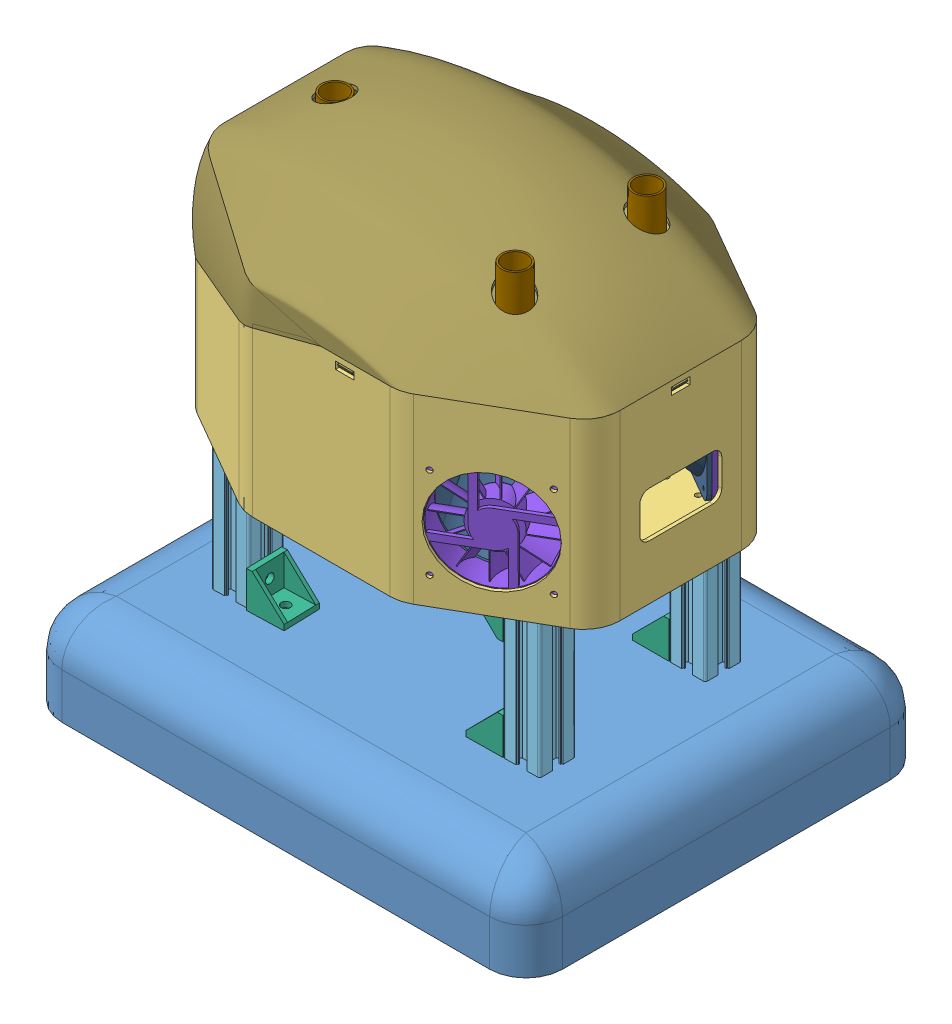
SolidWorks assembly Case_gases, configuration Predeterminado. Lengths in mm.
Overall size (275 288.19 220).
33 component instances, 12 part files, 60 mates.
Components (placement in the parent):
- Unitree_base-1: Unitree_base [Predeterminado] at origin size (275 50 220)
- arduino uno-1: arduino uno [Predeterminado] at (57.7112 103.65 32.423) size (53.34 15.25 74.93)
- Box_half-1: Box_half [Predeterminado] at (0 100 0) x (0 0 1) z (-1 0 0) size (170 100 225)
- Jetson Xavier NX DevKit LQ-1: Jetson Xavier NX DevKit LQ [Predeterminado] at (-44.3673 115.16 33.4874) x (0 0 -1) z (0 1 0) size (103 91.06 34.66)
- 2020_180mm-1: 2020_180mm [Valor predeterminado] at (80.2485 62.5 45.4943) x (-0.999929 0 0.011892) z (0 -1 0) size (20 20 75)
- Esquina2020-1: Esquina2020 [Predeterminado] at (60.2499 100 45.7322) x (0.011892 0 0.999929) z (0.999929 0 -0.011892) size (20 20 20)
- 2020_180mm-2: 2020_180mm [Valor predeterminado] at (-80.25 62.5 -45.75) x (1 0 0) z (0 -1 0) size (20 20 75)
- 2020_180mm-3: 2020_180mm [Valor predeterminado] at (80.25 62.5 -45.75) x (1 0 0) z (0 -1 0) size (20 20 75)
- 2020_180mm-4: 2020_180mm [Valor predeterminado] at (-80.281 62.5 45.0648) x (0.999533 0 -0.030564) z (0 -1 0) size (20 20 75)
- Esquina2020-2: Esquina2020 [Predeterminado] at (60.2499 25 45.7322) x (-0.011892 0 -0.999929) z (0.999929 0 -0.011892) size (20 20 20)
- Esquina2020-3: Esquina2020 [Predeterminado] at (-60.2903 100 44.4535) x (-0.030564 0 -0.999533) z (-0.999533 0 0.030564) size (20 20 20)
- Esquina2020-4: Esquina2020 [Predeterminado] at (-60.2493 25 45.7958) x (0.030564 0 0.999533) z (-0.999533 0 0.030564) size (20 20 20)
- Esquina2020-5: Esquina2020 [Predeterminado] at (60.25 25 -45.75) x (0 0 -1) z (1 0 0) size (20 20 20)
- Esquina2020-6: Esquina2020 [Predeterminado] at (-60.25 25 -45.75) x (0 0 1) z (-1 0 0) size (20 20 20)
- Esquina2020-7: Esquina2020 [Predeterminado] at (-60.25 100 -45.75) x (0 0 -1) z (-1 0 0) size (20 20 20)
- Esquina2020-8: Esquina2020 [Predeterminado] at (60.25 100 -45.75) x (0 0 1) z (1 0 0) size (20 20 20)
- tca9548a-1: tca9548a [Predeterminado] at (13.0283 102.399 -58.6097) size (21.5 2.4 31.5)
- 60x60x15 12V fan-2: 60x60x15 12V fan [Default] at (68.7162 145.2772 -50.6487) x (-0.866025 0 -0.5) z (0.5 0 -0.866025) size (60 60 15)
- 60x60x15 12V fan-3: 60x60x15 12V fan [Default] at (76.2162 145.2772 63.639) x (-0.866025 0 0.5) z (-0.5 0 -0.866025) size (60 60 15)
- Sub_salida_aire-1: Sub_salida_aire [Predeterminado] at (66.6795 140 51.8246) x (0 1 0) z (-0.866025 0 0.5) size (137.24 27.54 60.72)
  - ducto_sensor-1: ducto_sensor [Predeterminado] at (70 18 0) x (0 0 -1) z (0 1 0) size (35.49 78 18.62)
  - ducto_ventilador-1: ducto_ventilador [Predeterminado] at origin size (63.93 27.54 60.72)
  - sgp30-1: sgp30 [Predeterminado] at (50 21 -5.5) x (1 0 0) z (0 0 -1) size (24 8 27)
- Sub_salida_aire-2: Sub_salida_aire [Predeterminado] at (66.6795 140 -51.8246) x (0 1 0) z (0.866025 0 0.5) size (137.24 27.54 60.72)
  - ducto_sensor-1: ducto_sensor [Predeterminado] at (70 18 0) x (0 0 -1) z (0 1 0) size (35.49 78 18.62)
  - ducto_ventilador-1: ducto_ventilador [Predeterminado] at origin size (63.93 27.54 60.72)
  - sgp30-1: sgp30 [Predeterminado] at (50 21 -5.5) x (1 0 0) z (0 0 -1) size (24 8 27)
- head_cover-1: head_cover [Predeterminado] at (0 200 0) x (0 0 1) z (-1 0 0) size (174.79 93.34 229.98)
- Sub_salida_aire-3: Sub_salida_aire [Predeterminado] at (-95.5 135 0) x (0 1 0) z (0 0 -1) size (137.24 27.54 60.72)
  - ducto_sensor-1: ducto_sensor [Predeterminado] at (70 18 0) x (0 0 -1) z (0 1 0) size (35.49 78 18.62)
  - ducto_ventilador-1: ducto_ventilador [Predeterminado] at origin size (63.93 27.54 60.72)
  - sgp30-1: sgp30 [Predeterminado] at (50 21 -5.5) x (1 0 0) z (0 0 -1) size (24 8 27)
- 60x60x15 12V fan-4: 60x60x15 12V fan [Default] at (-110.5 140.2772 2.3518) x (0 0 -1) z (1 0 0) size (60 60 15)
Mates (geometry in assembly coordinates):
- Coincidente1: coincident aligned: plane of Unitree_base-1 through (0 0 0) normal (0 1 0); plane of assembly through (0 0 0) normal (0 1 0)
- Coincidente2: coincident aligned: plane of Unitree_base-1 through (0 0 0) normal (0 0 1); plane of assembly through (0 0 0) normal (0 0 1)
- Coincidente3: coincident aligned: plane of Unitree_base-1 through (0 0 0) normal (1 0 0); plane of assembly through (0 0 0) normal (1 0 0)
- Concéntrica1: concentric anti-aligned: circle of Unitree_base-1; circle of Box_half-1
- Concéntrica3: concentric anti-aligned: circle of Unitree_base-1; circle of Box_half-1
- Coincidente4: coincident anti-aligned: plane of Box_half-1 through (37.859 100 65) normal (0 -1 0); plane of 2020_180mm-1 through (80.2485 100 45.4943) normal (0 1 0)
- Coincidente5: coincident anti-aligned: plane of Unitree_base-1 through (-117.5 25 90) normal (0 1 0); plane of 2020_180mm-4 through (-80.281 25 45.0648) normal (0 -1 0)
- Coincidente6: coincident anti-aligned: plane of 2020_180mm-4 through (-70.2857 25 44.7592) normal (0.999533 0 -0.030564); plane of Esquina2020-4 through (-70.5503 28 36.1062) normal (-0.999533 0 0.030564)
- Coincidente7: coincident anti-aligned: plane of Unitree_base-1 through (-117.5 25 90) normal (0 1 0); plane of Esquina2020-4 through (-60.2493 25 45.7958) normal (0 -1 0)
- Concéntrica4: concentric aligned: circle of Unitree_base-1; circle of Esquina2020-4
- Coincidente8: coincident anti-aligned: plane of 2020_180mm-4 through (-70.2857 25 44.7592) normal (0.999533 0 -0.030564); plane of Esquina2020-3 through (-69.98 97 54.7545) normal (-0.999533 0 0.030564)
- Coincidente9: coincident aligned: plane of 2020_180mm-4 through (-80.281 100 45.0648) normal (0 1 0); plane of Esquina2020-3 through (-60.2903 100 44.4535) normal (0 1 0)
- Coincidente10: coincident aligned: plane of 2020_180mm-4 through (-79.9754 25 55.0601) normal (0.030564 0 0.999533); plane of Esquina2020-3 through (-49.9894 97 54.1432) normal (0.030564 0 0.999533)
- Coincidente11: coincident anti-aligned: plane of Box_half-1 through (37.859 100 65) normal (0 -1 0); plane of Esquina2020-3 through (-60.2903 100 44.4535) normal (0 1 0)
- Coincidente12: coincident anti-aligned: plane of 2020_180mm-1 through (70.2492 25 45.6132) normal (-0.999929 0 0.011892); plane of Esquina2020-2 through (70.3681 28 55.6125) normal (0.999929 0 -0.011892)
- Coincidente13: coincident aligned: plane of 2020_180mm-1 through (80.1296 25 35.495) normal (-0.011892 0 -0.999929); plane of Esquina2020-2 through (50.1317 28 35.8518) normal (-0.011892 0 -0.999929)
- Coincidente14: coincident anti-aligned: plane of Unitree_base-1 through (-117.5 25 90) normal (0 1 0); plane of Esquina2020-2 through (60.2499 25 45.7322) normal (0 -1 0)
- Concéntrica5: concentric aligned: circle of Unitree_base-1; circle of Esquina2020-2
- Coincidente15: coincident anti-aligned: plane of 2020_180mm-1 through (70.2492 25 45.6132) normal (-0.999929 0 0.011892); plane of Esquina2020-1 through (70.1303 97 35.6139) normal (0.999929 0 -0.011892)
- Coincidente16: coincident anti-aligned: plane of Box_half-1 through (37.859 100 65) normal (0 -1 0); plane of Esquina2020-1 through (60.2499 100 45.7322) normal (0 1 0)
- Coincidente17: coincident aligned: plane of 2020_180mm-1 through (80.3674 25 55.4936) normal (0.011892 0 0.999929); plane of Esquina2020-1 through (50.3695 97 55.8504) normal (0.011892 0 0.999929)
- Coincidente18: coincident anti-aligned: plane of Box_half-1 through (37.859 100 65) normal (0 -1 0); plane of 2020_180mm-3 through (80.25 100 -45.75) normal (0 1 0)
- Coincidente19: coincident anti-aligned: plane of Box_half-1 through (37.859 100 65) normal (0 -1 0); plane of 2020_180mm-2 through (-80.25 100 -45.75) normal (0 1 0)
- Coincidente20: coincident anti-aligned: plane of 2020_180mm-3 through (70.25 25 -45.75) normal (-1 0 0); plane of Esquina2020-5 through (70.25 28 -35.75) normal (1 0 0)
- Coincidente21: coincident anti-aligned: plane of Unitree_base-1 through (-117.5 25 90) normal (0 1 0); plane of Esquina2020-5 through (60.25 25 -45.75) normal (0 -1 0)
- Coincidente22: coincident aligned: plane of 2020_180mm-3 through (80.25 25 -55.75) normal (0 0 -1); plane of Esquina2020-5 through (50.25 28 -55.75) normal (0 0 -1)
- Coincidente23: coincident anti-aligned: plane of 2020_180mm-2 through (-70.25 25 -45.75) normal (1 0 0); plane of Esquina2020-6 through (-70.25 28 -55.75) normal (-1 0 0)
- Coincidente24: coincident anti-aligned: plane of Unitree_base-1 through (-117.5 25 90) normal (0 1 0); plane of Esquina2020-6 through (-60.25 25 -45.75) normal (0 -1 0)
- Coincidente25: coincident aligned: plane of 2020_180mm-2 through (-80.25 25 -55.75) normal (0 0 -1); plane of Esquina2020-6 through (-50.25 28 -55.75) normal (0 0 -1)
- Concéntrica6: concentric aligned: circle of Unitree_base-1; circle of Esquina2020-5
- Concéntrica7: concentric aligned: circle of Unitree_base-1; circle of Esquina2020-6
- Coincidente26: coincident anti-aligned: plane of 2020_180mm-3 through (70.25 25 -45.75) normal (-1 0 0); plane of Esquina2020-8 through (70.25 97 -55.75) normal (1 0 0)
- Coincidente27: coincident anti-aligned: plane of Box_half-1 through (37.859 100 65) normal (0 -1 0); plane of Esquina2020-8 through (60.25 100 -45.75) normal (0 1 0)
- Coincidente28: coincident aligned: plane of 2020_180mm-3 through (80.25 25 -55.75) normal (0 0 -1); plane of Esquina2020-8 through (50.25 97 -55.75) normal (0 0 -1)
- Coincidente29: coincident anti-aligned: plane of 2020_180mm-2 through (-70.25 25 -45.75) normal (1 0 0); plane of Esquina2020-7 through (-70.25 97 -35.75) normal (-1 0 0)
- Coincidente30: coincident anti-aligned: plane of Box_half-1 through (37.859 100 65) normal (0 -1 0); plane of Esquina2020-7 through (-60.25 100 -45.75) normal (0 1 0)
- Coincidente31: coincident aligned: plane of 2020_180mm-2 through (-80.25 25 -55.75) normal (0 0 -1); plane of Esquina2020-7 through (-50.25 97 -55.75) normal (0 0 -1)
- Coincidente32: coincident anti-aligned: plane of Box_half-1 through (37.859 102 65) normal (0 1 0); plane of Jetson Xavier NX DevKit LQ-1 through (-44.3673 102 33.4874) normal (0 -1 0)
- Coincidente33: coincident anti-aligned: plane of arduino uno-1 through (4.3712 102 32.423) normal (0 -1 0); plane of Box_half-1 through (37.859 102 65) normal (0 1 0)
- Coincidente46: coincident anti-aligned: plane of 60x60x15 12V fan-3 through (68.7162 145.2772 50.6487) normal (-0.5 0 -0.866025); plane of Sub_salida_aire-1/ducto_ventilador-1 through (45.0289 115 64.3246) normal (0.5 0 0.866025)
- Concéntrica20: concentric anti-aligned: circle of 60x60x15 12V fan-2; circle of Sub_salida_aire-2/ducto_ventilador-1
- Concéntrica21: concentric anti-aligned: circle of 60x60x15 12V fan-2; circle of Sub_salida_aire-2/ducto_ventilador-1
- Coincidente47: coincident anti-aligned: plane of 60x60x15 12V fan-2 through (68.7162 145.2772 -50.6487) normal (-0.5 0 0.866025); plane of Sub_salida_aire-2/ducto_ventilador-1 through (88.3301 115 -39.3246) normal (0.5 0 -0.866025)
- Concéntrica26: concentric aligned: circle of 60x60x15 12V fan-3; circle of Sub_salida_aire-1/ducto_ventilador-1
- Concéntrica31: concentric anti-aligned: circle of Box_half-1; circle of 60x60x15 12V fan-3
- Concéntrica32: concentric aligned: circle of 60x60x15 12V fan-3; circle of Sub_salida_aire-1/ducto_ventilador-1
- Concéntrica33: concentric anti-aligned: circle of Box_half-1; circle of 60x60x15 12V fan-3
- Coincidente51: coincident anti-aligned: plane of Box_half-1 through (46.859 200 80.5885) normal (-0.5 0 -0.866025); plane of 60x60x15 12V fan-3 through (76.2162 145.2772 63.639) normal (0.5 0 0.866025)
- Concéntrica34: concentric anti-aligned: circle of Box_half-1; circle of 60x60x15 12V fan-2
- Concéntrica35: concentric anti-aligned: circle of Box_half-1; circle of 60x60x15 12V fan-2
- Coincidente52: coincident anti-aligned: plane of Box_half-1 through (46.859 200 -80.5885) normal (-0.5 0 0.866025); plane of 60x60x15 12V fan-2 through (76.2162 145.2772 -63.639) normal (0.5 0 -0.866025)
- Coincidente55: coincident anti-aligned: plane of Box_half-1 through (110.5 200 -33.453) normal (-1 0 0); plane of head_cover-1 through (110.5 169.8557 33.453) normal (1 0 0)
- Coincidente56: coincident anti-aligned: plane of Box_half-1 through (37.859 200 -83) normal (0 0 1); plane of head_cover-1 through (37.859 169.8557 -83) normal (0 0 -1)
- Coincidente57: coincident anti-aligned: plane of Box_half-1 through (37.859 200 65) normal (0 1 0); plane of head_cover-1 through (0 200 -85.005) normal (0 -1 0)
- Concéntrica36: concentric anti-aligned: circle of Box_half-1; circle of 60x60x15 12V fan-4
- Concéntrica37: concentric anti-aligned: circle of Box_half-1; circle of 60x60x15 12V fan-4
- Coincidente58: coincident anti-aligned: plane of Box_half-1 through (-110.5 200 -33.453) normal (1 0 0); plane of 60x60x15 12V fan-4 through (-110.5 140.2772 2.3518) normal (-1 0 0)
- Concéntrica38: concentric aligned: circle of Sub_salida_aire-3/ducto_ventilador-1; circle of 60x60x15 12V fan-4
- Concéntrica39: concentric aligned: circle of Sub_salida_aire-3/ducto_ventilador-1; circle of 60x60x15 12V fan-4
- Coincidente59: coincident anti-aligned: plane of Sub_salida_aire-3/ducto_ventilador-1 through (-95.5 110 -25) normal (-1 0 0); plane of 60x60x15 12V fan-4 through (-95.5 140.2772 2.3518) normal (1 0 0)
